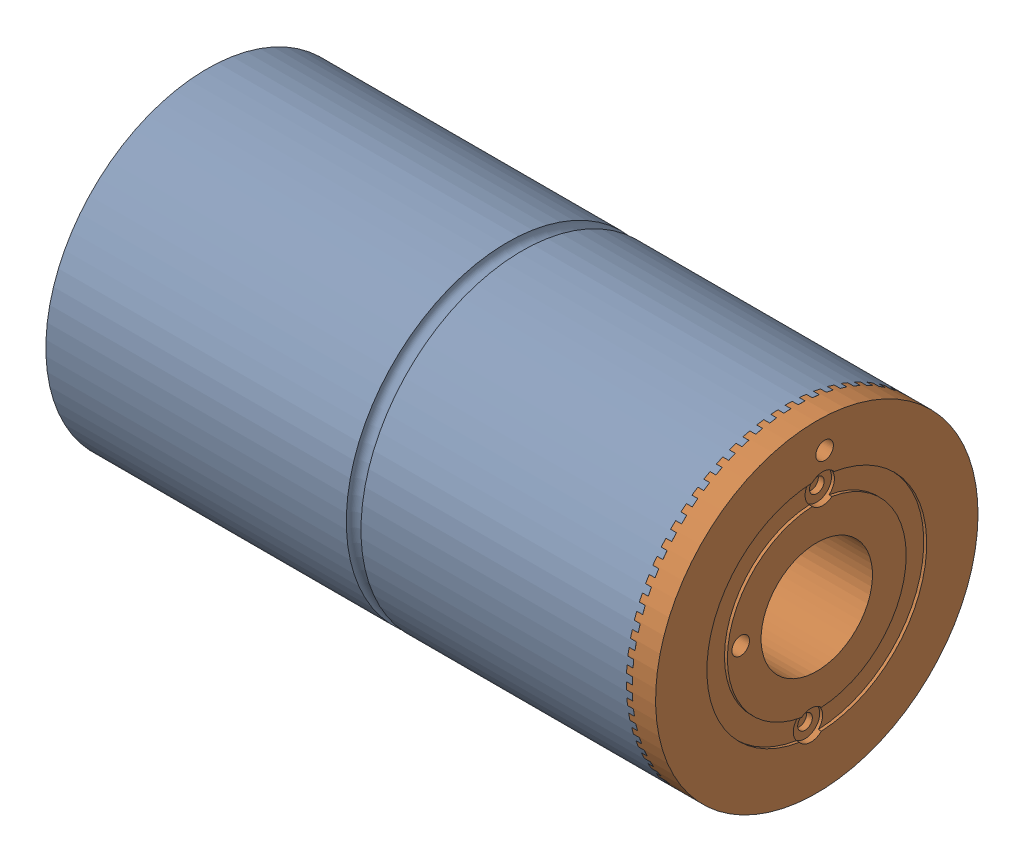
SolidWorks assembly Assem4, configuration Default. Lengths in mm.
Overall size (208 116.32 116.32).
3 component instances, 3 part files, 4 mates.
Components (placement in the parent):
- Part1.2-1: Part1.2 [Default] at (-151.5482 8.3174 21.5505) size (200 110 110)
- Part2.3-1: Part2.3 [Default] at (56.4518 8.3174 21.5505) x (-1 0 0) z (0 -0.059206 -0.998246) size (200 110 110)
- Part3-1: Part3 [Default] at (50.4518 8.3174 21.5505) x (0 0 -1) z (0 1 0) size (75 192 75)
Mates (geometry in assembly coordinates):
- Concentric1: concentric aligned: circle of Part2.3-1; circle of Part3-1
- Coincident9: coincident anti-aligned: plane of Part2.3-1 through (50.4518 8.3174 21.5505) normal (-1 0 0); plane of Part3-1 through (50.4518 8.3174 21.5505) normal (1 0 0)
- Concentric3: concentric aligned: cylinder of Part1.2-1; cylinder of Part3-1 through (-141.5482 8.3174 21.5505) axis (1 0 0) radius 30.5
- Coincident12: coincident anti-aligned: plane of Part1.2-1 through (-141.5482 8.3174 21.5505) normal (1 0 0); plane of Part3-1 through (-141.5482 8.3174 21.5505) normal (-1 0 0)
